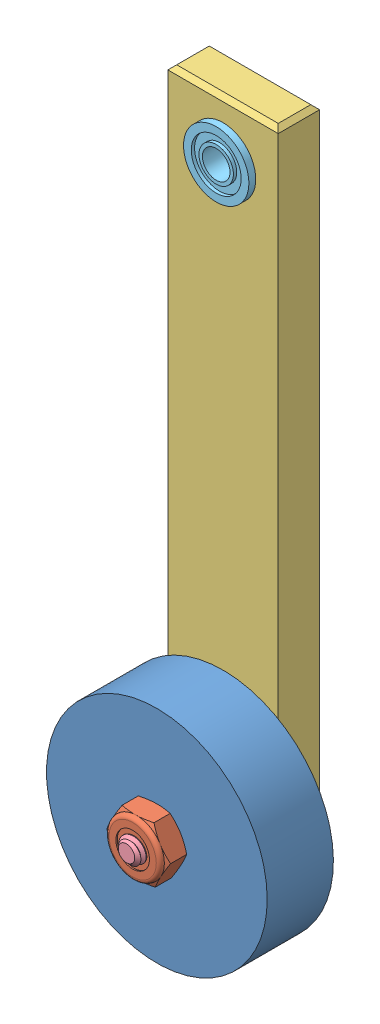
SolidWorks assembly bottom_link_assy, configuration Default. Lengths in mm.
Overall size (31.92 85.81 16.92).
6 component instances, 5 part files, 15 mates.
Components (placement in the parent):
- Mass_blank-1: Mass_blank [Default] at (0 -69.85 4.7625) x (0.9527 0.303914 0) z (0 0 1) size (25.4 25.4 7.62)
- 4_40_THIN_LOCKNUT_90633A005-1: 4_40_THIN_LOCKNUT_90633A005 [90633A005] at (0 -69.85 12.3825) x (0.853828 0.520556 0) z (0.520556 -0.853828 0) size (6.35 2.86 7.33)
- bottom_link-1: bottom_link [Default] at (0 -6.35 4.7625) x (0 1 0) z (-1 0 0) size (76.2 4.76 12.7)
- 4_40-625-countersunk-stainless-92210a112-1: 4_40-625-countersunk-stainless-92210a112 [92210A112] at (0 -69.85 0) x (-0.923728 -0.383049 0) z (0 0 -1) size (6.48 6.48 16.22)
- FR144-ZZ-1: FR144-ZZ [Default] at (0 -6.35 2.7464) size (7.52 7.52 2.8)
- FR144-ZZ-2: FR144-ZZ [Default] at (0 -6.35 2.0161) x (-0.923728 -0.383049 0) z (0 0 -1) size (7.52 7.52 2.8)
Mates (geometry in assembly coordinates):
- Coincident40: coincident anti-aligned: plane of Mass_blank-1 through (0 -69.85 12.3825) normal (0 0 1); plane of 4_40_THIN_LOCKNUT_90633A005-1 through (-5.5736 -66.8073 12.3825) normal (0 0 -1)
- Concentric30: concentric aligned: cylinder of Mass_blank-1 through (0 -69.85 12.3825) axis (0 0 -1) radius 12.7; cylinder of 4_40_THIN_LOCKNUT_90633A005-1 through (0 -69.85 16.4306) axis (0 0 -1) radius 1.9297
- Concentric31: concentric anti-aligned: cylinder of Mass_blank-1 through (0 -69.85 12.3825) axis (0 0 1) radius 1.632; cylinder of bottom_link-1 through (0 -69.85 0) axis (0 0 -1) radius 1.632
- Coincident41: coincident anti-aligned: plane of bottom_link-1 through (0 -6.35 4.7625) normal (0 0 1); plane of Mass_blank-1 through (0 -69.85 4.7625) normal (0 0 -1)
- Coincident42: coincident anti-aligned: plane of bottom_link-1 through (0 0 0) normal (0 0 -1); plane of ? through (1.8032 -65.5164 0) normal (0 0 1)
- Concentric32: concentric aligned: cylinder of bottom_link-1 through (0 -63.5 0) axis (0 0 -1) radius 1.632; cylinder of ? through (0 -63.5 -1.4986) axis (0 0 -1) radius 2.7051
- Symmetric1: symmetric aligned: plane of bottom_link-1 through (-6.35 -6.35 0) normal (-1 0 0); plane of bottom_link-1 through (6.35 -6.35 0) normal (1 0 0); plane of assembly through (0 0 0) normal (1 0 0)
- Coincident43: coincident anti-aligned: plane of bottom_link-1 through (0 -6.35 0) normal (0 0 -1); plane of assembly through (0 0 0) normal (0 0 1)
- Coincident44: coincident aligned: plane of bottom_link-1 through (0 0 0) normal (0 1 0); plane of assembly through (0 0 0) normal (0 1 0)
- Concentric33: concentric aligned: cylinder of bottom_link-1 through (0 -69.85 0) axis (0 0 -1) radius 1.632; cylinder of 4_40-625-countersunk-stainless-92210a112-1 through (0 -69.85 0) axis (0 0 -1) radius 3.2385
- Coincident45: coincident aligned: plane of bottom_link-1 through (0 -6.35 0) normal (0 0 -1); plane of 4_40-625-countersunk-stainless-92210a112-1 through (0.5448 -71.1639 0) normal (0 0 -1)
- Coincident46: coincident aligned: plane of bottom_link-1 through (0 -6.35 0) normal (0 0 -1); circle of FR144-ZZ-2
- Concentric34: concentric anti-aligned: cylinder of bottom_link-1 through (0 -6.35 4.7625) axis (0 0 -1) radius 3.1623; cylinder of FR144-ZZ-2 through (0 -6.35 0) axis (0 0 1) radius 3.175
- Coincident47: coincident anti-aligned: plane of bottom_link-1 through (0 -6.35 4.7625) normal (0 0 1); plane of FR144-ZZ-1 through (0 -6.35 4.7625) normal (0 0 -1)
- Concentric35: concentric aligned: cylinder of bottom_link-1 through (0 -6.35 4.7625) axis (0 0 -1) radius 3.1623; cylinder of FR144-ZZ-1 through (0 -6.35 4.7625) axis (0 0 -1) radius 3.175
